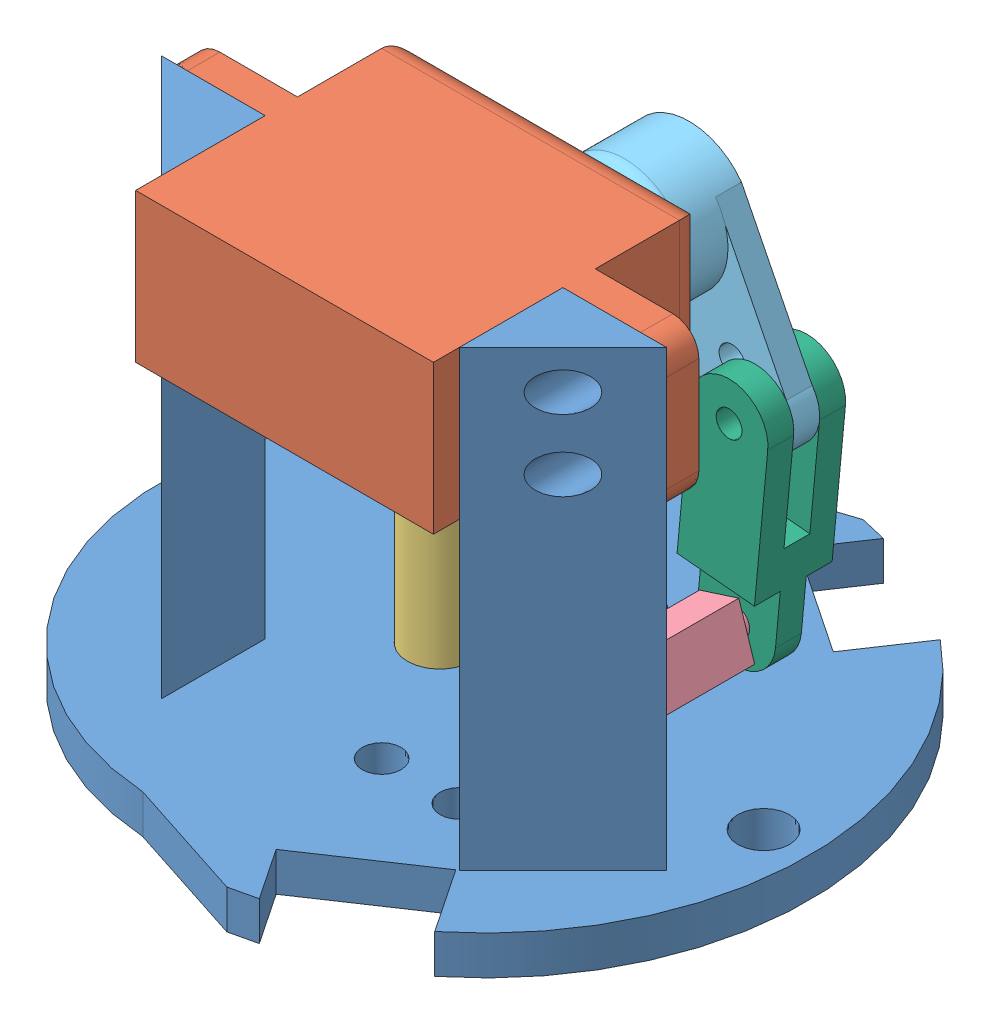
SolidWorks assembly Rückseite, configuration Standard. Lengths in mm.
Overall size (50 39.6 49.14).
6 component instances, 6 part files, 13 mates.
Components (placement in the parent):
- Backside-1: Backside [Standard] at (-0.7502 -6.4244 50) size (50 38 49.14)
- servo-1: servo [Standard] at (-7.7502 31.5756 66.5) x (1 0 0) z (0 1 0) size (39 24.75 11.5)
- Drücker-1: Drücker [Standard] at (-2.5879 -6.7842 21.7522) size (5 25 5)
- Hebel-1: Hebel [Standard] at (9.2498 10.5756 49) x (0.889385 -0.457159 0) z (0 0 1) size (28.49 10.74 12.5)
- Servo-Arm-1: Servo-Arm [Standard] at (8.2498 25.8256 39.75) x (0.590102 -0.807328 0) z (-0.807328 -0.590102 0) size (20 6 10)
- Hebel2-1: Hebel2 [Standard] at (13.9281 1.2034 39.75) x (0.09353 0.995616 0) z (0.995616 -0.09353 0) size (21 6 6)
Mates (geometry in assembly coordinates):
- Konzentrisch1: concentric aligned: cylinder of Drücker-1 through (-0.7502 18.2158 50) axis (0 -1 0) radius 2.5; cylinder of Backside-1 through (-0.7502 -3.4244 50) axis (0 -1 0) radius 2.5
- Konzentrisch2: concentric anti-aligned: cylinder of Backside-1 through (9.2498 10.5756 42.5) axis (0 0 1) radius 1; cylinder of Hebel-1 through (9.2498 10.5756 51) axis (0 0 -1) radius 1
- Deckungsgleich1: coincident anti-aligned: plane of Backside-1 through (6.7498 13.5756 51) normal (0 0 -1); plane of Hebel-1 through (9.2498 10.5756 51) normal (0 0 1)
- Parallel1: parallel anti-aligned: plane of Drücker-1 through (-3.7502 10.2158 49) normal (0 0 1); plane of Hebel-1 through (9.2498 10.5756 49) normal (0 0 -1)
- Tangential1: tangent anti-aligned: cylinder of Drücker-1 through (-0.7502 15.7158 46) axis (0 0 1) radius 1; plane of Hebel-1 through (8.7927 9.6862 51) normal (0.457159 0.889385 0)
- Deckungsgleich5: coincident anti-aligned: plane of servo-1 through (8.2498 25.8256 41.75) normal (0 0 -1); plane of Servo-Arm-1 through (8.2498 25.8256 41.75) normal (0 0 1)
- Konzentrisch3: concentric anti-aligned: cylinder of servo-1 through (8.2498 25.8256 41.75) axis (0 0 1) radius 3; cylinder of Servo-Arm-1 through (8.2498 25.8256 45.75) axis (0 0 -1) radius 3
- Deckungsgleich6: coincident anti-aligned: plane of Backside-1 through (-7.7502 31.5756 64.5) normal (1 0 0); plane of servo-1 through (-7.7502 31.5756 45.5) normal (-1 0 0)
- Deckungsgleich7: coincident anti-aligned: plane of Backside-1 through (-7.7502 31.5756 56.5) normal (0 0 -1); plane of servo-1 through (23.2498 31.5756 56.5) normal (0 0 1)
- Deckungsgleich11: coincident aligned: plane of Backside-1 through (-0.7502 31.5756 50) normal (0 1 0); plane of servo-1 through (-7.7502 31.5756 45.5) normal (0 1 0)
- Deckungsgleich9: coincident anti-aligned: plane of Servo-Arm-1 through (8.2498 25.8256 39.75) normal (0 0 -1); plane of Hebel2-1 through (13.9281 1.2034 39.75) normal (0 0 1)
- Deckungsgleich10: coincident anti-aligned: circle of Servo-Arm-1; cylinder of Hebel2-1 through (15.331 16.1377 41.75) axis (0 0 -1) radius 1
- Konzentrisch4: concentric anti-aligned: cylinder of Hebel-1 through (13.9281 1.2034 38.5) axis (0 0 1) radius 1; cylinder of Hebel2-1 through (13.9281 1.2034 41.75) axis (0 0 -1) radius 1
